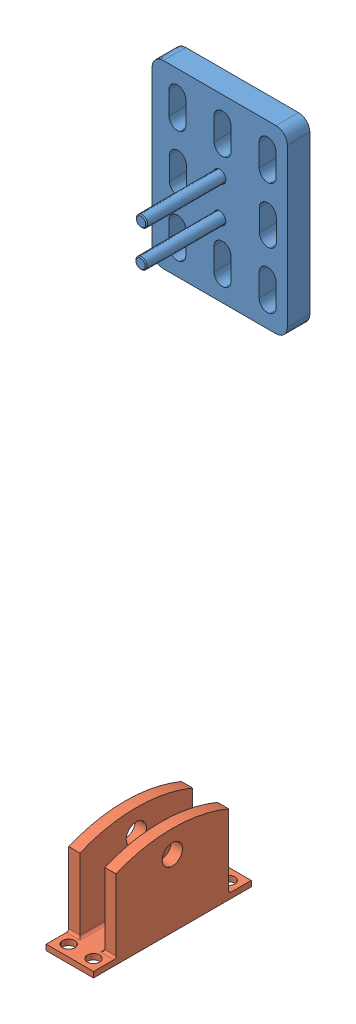
SolidWorks assembly Brake pedal assem, configuration Default. Lengths in mm.
Overall size (60 302 77.33).
2 component instances, 2 part files, 1 mates.
Components (placement in the parent):
- Brake pedal with support and bolts-1: Brake pedal with support and bolts [Default] at (-62.7745 2.9065 43.821) size (60 80 46.4)
- Base Pedal Interface-1: Base Pedal Interface [Default] at (-56.1775 -152.3123 -3.2287) size (21 40 70)
Mates (geometry in assembly coordinates):
- Coincident1: coincident: circle of Brake pedal with support and bolts-1; circle of Base Pedal Interface-1
